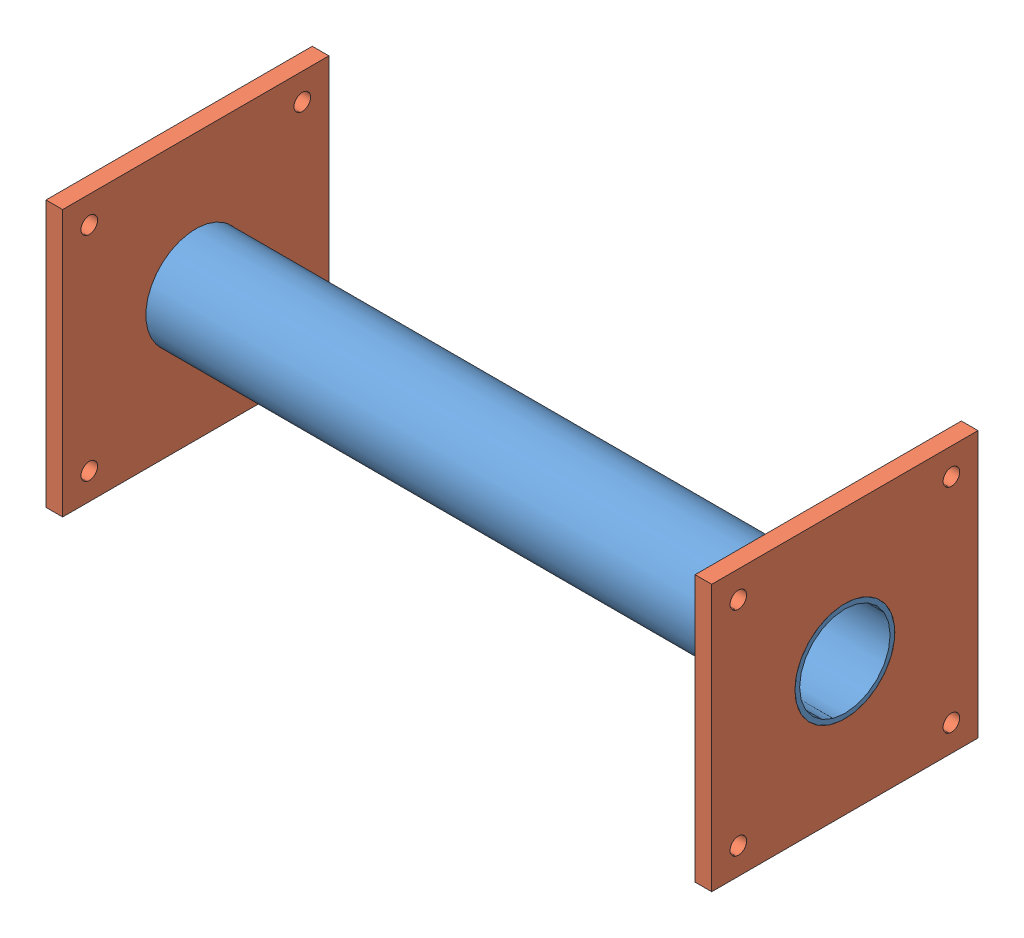
SolidWorks assembly Heater Barrel Assm, configuration Default. Lengths in mm.
Overall size (127 50.8 50.8).
3 component instances, 2 part files, 6 mates.
Components (placement in the parent):
- printing barrel-1: printing barrel [Default<As Machined>] at (-68.0528 6.181 -1.7968) size (127 19.05 19.05)
- barrel flange-2: barrel flange [Default] at (-64.8778 -19.219 -27.1968) x (0 0 1) z (-1 0 0) size (50.8 50.8 3.17)
- barrel flange-4: barrel flange [Default] at (55.7722 -19.219 23.6032) x (0 0 -1) z (1 0 0) size (50.8 50.8 3.17)
Mates (geometry in assembly coordinates):
- Concentric2: concentric anti-aligned: cylinder of printing barrel-1 through (-68.0528 6.181 -1.7968) axis (-1 0 0) radius 8.636; cylinder of barrel flange-2 through (-68.0528 6.181 -1.7968) axis (1 0 0) radius 9.525
- Coincident3: coincident aligned: plane of printing barrel-1 through (-68.0528 6.181 -10.4328) normal (-1 0 0); plane of barrel flange-2 through (-68.0528 31.581 -27.1968) normal (-1 0 0)
- Parallel2: parallel aligned: plane of barrel flange-2 through (-68.0528 31.581 -27.1968) normal (0 1 0); plane of assembly through (0 0 0) normal (0 1 0)
- Concentric4: concentric anti-aligned: cylinder of printing barrel-1 through (-68.0528 6.181 -1.7968) axis (-1 0 0) radius 8.636; circle of barrel flange-4
- Parallel4: parallel anti-aligned: line of barrel flange-2 through (-64.8778 31.581 -27.1968) axis (0 -1 0); line of barrel flange-4 through (55.7722 -19.219 -27.1968) axis (0 1 0)
- Coincident4: coincident aligned: plane of printing barrel-1 through (58.9472 6.181 -11.3218) normal (1 0 0); plane of barrel flange-4 through (58.9472 31.581 23.6032) normal (1 0 0)
